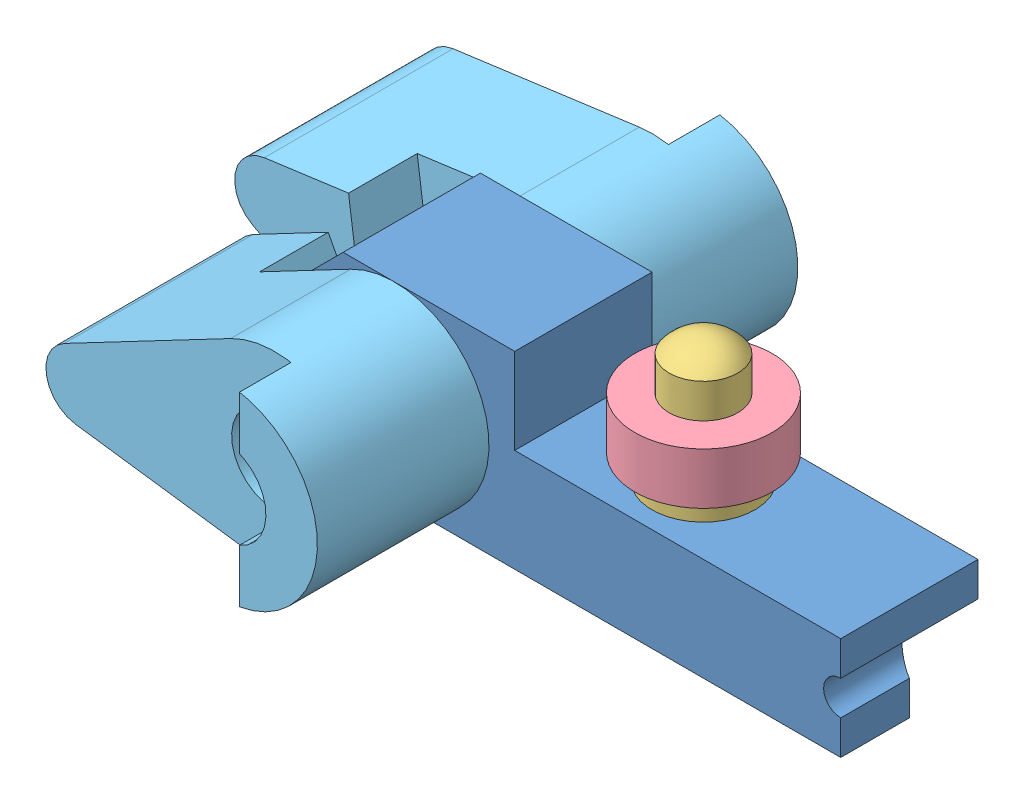
SolidWorks assembly pene lançant, configuration Défaut. Lengths in mm.
Overall size (40.25 15.66 28).
6 component instances, 5 part files, 14 mates.
Components (placement in the parent):
- Pièce5-1: Pièce5 [Défaut] at (-12.8916 -3.2369 -4) size (32 11 8)
- Pièce4-1: Pièce4 [Défaut] at (-6.8916 2.2631 10.5) x (0 0 -1) z (1 0 0) size (21 6 6)
- axe de noix-1: axe de noix [Défaut] at (7.1084 -5.2369 0) x (0 1 0) z (0 0 1) size (15.4 6 6)
- Pièce6-1: Pièce6 [Défaut] at (7.1084 4.1631 0) x (0.982348 0 0.187064) z (0 1 0) size (8 8 3)
- Pièce3-3: Pièce3 [Défaut] at (-6.8916 2.2631 -14) x (0.984808 -0.173648 0) z (0 0 1) size (19 11 14)
- Pièce3-4: Pièce3 [Défaut] at (-6.8916 2.2631 14) x (0.984808 0.173648 0) z (0 0 -1) size (19 11 14)
Mates (geometry in assembly coordinates):
- Coaxiale1: concentric anti-aligned: cylinder of Pièce5-1 through (-6.8916 2.2631 4) axis (0 0 -1) radius 3; cylinder of Pièce4-1 through (-6.8916 2.2631 65.3246) axis (0 0 1) radius 3
- Coïncidente1: coincident aligned: plane of Pièce5-1 through (-12.8916 2.7631 4) normal (0 0 1); plane of Pièce4-1 through (-6.8916 4.7631 4) normal (0 0 1)
- Coaxiale5: concentric anti-aligned: cylinder of Pièce5-1 through (7.1084 7.7631 0) axis (0 -1 0) radius 2; cylinder of axe de noix-1 through (7.1084 9.1631 0) axis (0 1 0) radius 2
- Coïncidente4: coincident anti-aligned: plane of Pièce5-1 through (19.1084 2.7631 4) normal (0 1 0); plane of axe de noix-1 through (5.1084 2.7631 0) normal (0 -1 0)
- Coaxiale6: concentric anti-aligned: cylinder of axe de noix-1 through (7.1084 9.1631 0) axis (0 1 0) radius 2; cylinder of Pièce6-1 through (7.1084 7.1631 0) axis (0 -1 0) radius 2
- Coïncidente5: coincident anti-aligned: plane of axe de noix-1 through (4.1084 4.1631 0) normal (0 1 0); plane of Pièce6-1 through (7.1084 4.1631 0) normal (0 -1 0)
- Coaxiale2: concentric anti-aligned: cylinder of Pièce4-1 through (-6.8916 2.2631 65.3246) axis (0 0 1) radius 2.5; cylinder of Pièce3-3 through (-6.8916 2.2631 0) axis (0 0 -1) radius 2.5
- Coïncidente2: coincident anti-aligned: plane of Pièce5-1 through (-12.8916 2.7631 -4) normal (0 0 -1); plane of Pièce3-3 through (-6.8916 2.2631 -4) normal (0 0 1)
- Parallèle1: parallel aligned: plane of Pièce5-1 through (-12.8916 -3.2369 4) normal (-1 0 0); plane of Pièce3-3 through (-5.9366 5.9476 -11) normal (-1 0 0)
- Coaxiale4: concentric aligned: cylinder of Pièce4-1 through (-6.8916 2.2631 65.3246) axis (0 0 1) radius 2.5; cylinder of Pièce3-4 through (-6.8916 2.2631 0) axis (0 0 1) radius 2.5
- Coïncidente3: coincident anti-aligned: plane of Pièce5-1 through (-12.8916 2.7631 4) normal (0 0 1); plane of Pièce3-4 through (-6.8916 2.2631 4) normal (0 0 -1)
- Coïncidente6: coincident aligned: plane of Pièce3-3 through (-5.9366 5.9476 -11) normal (-1 0 0); plane of Pièce3-4 through (-5.9366 -1.4213 11) normal (-1 0 0)
- Coïncidente9: coincident aligned: plane of Pièce3-3 through (-7.6303 7.7133 0) normal (-0.134314 0.990939 0); plane of Pièce3-4
- Parallèle2: parallel aligned: plane of Pièce5-1 through (-12.8916 -3.2369 4) normal (-1 0 0); plane of Pièce3-4 through (-5.9366 -1.4213 11) normal (-1 0 0)
